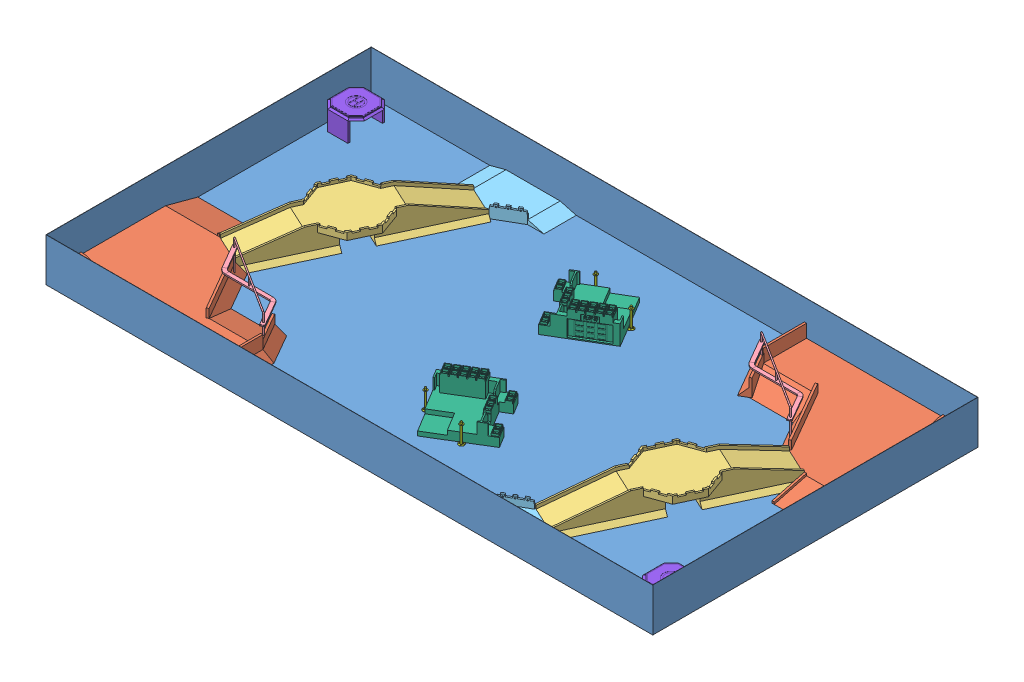
SolidWorks assembly RM场地总装, configuration 默认. Lengths in mm.
Overall size (28020 2000 15020).
17 component instances, 8 part files, 44 mates.
Components (placement in the parent):
- 场地底座-1: 场地底座 [默认] at (-5231.205 604.0435 28020) size (28020 2000 15020)
- 机器人启动区-1: 机器人启动区 [默认] at (-15231.205 614.0435 32770) x (0 0 1) z (-1 0 0) size (6992.82 1000 8400)
- 穿越桥-1: 穿越桥 [默认] at (-14265.56 1664.0435 26507.0583) x (-0.422618 0 0.906308) z (-0.906308 0 -0.422618) size (8806.06 1210 3000)
- 哨兵轨道-1: 哨兵轨道 [默认] at (-15148.1781 1894.0435 30872.3195) x (-0.5 0 -0.866025) z (0.866025 0 -0.5) size (4153.01 1720 2196.69)
- 关口-1: 关口 [默认] at (-11829.8568 614.0435 21918.3617) size (3992.82 610 2152.93)
- 关口-2: 关口 [默认] at (1367.4468 614.0435 34121.6383) x (-1 0 0) z (0 0 -1) size (3992.82 610 2152.93)
- 穿越桥-2: 穿越桥 [默认] at (3803.1499 1664.0435 29532.9417) x (0.422618 0 -0.906308) z (0.906308 0 0.422618) size (8806.06 1210 3000)
- 机器人启动区-2: 机器人启动区 [默认] at (4768.795 614.0435 23270) x (0 0 -1) z (1 0 0) size (6992.82 1000 8400)
- 哨兵轨道-2: 哨兵轨道 [默认] at (804.9132 1894.0435 22481.9287) x (-0.5 0 -0.866025) z (0.866025 0 -0.5) size (4153.01 1720 2196.69)
- rm资源岛-1: rm资源岛 [默认] at (-4093.3218 614.0435 31196.3435) x (-0.854584 0 0.519313) z (-0.519313 0 -0.854584) size (2750 1200 2570)
- rm资源岛-3: rm资源岛 [默认] at (-5345.3514 614.0435 24346.5388) x (0.859021 0 -0.51194) z (0.51194 0 0.859021) size (2750 1200 2570)
- 上岛立柱-1: 上岛立柱 [默认] at (-4055.4099 614.0435 23825.1634) x (0.859021 0 -0.51194) z (0.51194 0 0.859021) size (325 905 250)
- 四旋翼停机坪-1: 四旋翼停机坪 [默认] at (7918.795 1514.0435 33817.5787) x (0 0 -1) z (1 0 0) size (1700 1000 1700)
- 四旋翼停机坪-2: 四旋翼停机坪 [默认] at (-18381.205 1514.0435 22067.6477) x (0 0 -1) z (1 0 0) size (1700 1000 1700)
- 上岛立柱-2: 上岛立柱 [默认] at (-3321.3177 614.0435 32230.868) x (0.519313 0 0.854584) z (-0.854584 0 0.519313) size (325 905 250)
- 上岛立柱-3: 上岛立柱 [默认] at (-5378.7288 614.0435 31728.8001) x (-0.854584 0 0.519313) z (-0.519313 0 -0.854584) size (325 905 250)
- 上岛立柱-4: 上岛立柱 [默认] at (-6108.4243 614.0435 23305.4091) x (-0.51194 0 -0.859021) z (0.859021 0 -0.51194) size (325 905 250)
Mates (geometry in assembly coordinates):
- 重合2: coincident anti-aligned: plane of 机器人启动区-1 through (-15231.205 614.0435 32770) normal (0 -1 0); plane of 场地底座-1 through (-5231.205 614.0435 28020) normal (0 1 0)
- 重合3: coincident anti-aligned: plane of 场地底座-1 through (8768.795 2604.0435 35520) normal (0 0 -1); plane of 机器人启动区-1 through (-19231.205 1014.0435 35520) normal (0 0 1)
- 重合4: coincident anti-aligned: plane of 场地底座-1 through (-19231.205 2604.0435 20520) normal (1 0 0); plane of 机器人启动区-1 through (-19231.205 1014.0435 30020) normal (-1 0 0)
- 平行1: parallel aligned: plane of 场地底座-1 through (8778.795 2604.0435 35530) normal (0 0 1); plane of 哨兵轨道-1 through (-14217.7006 1864.0435 32278.9538) normal (0 0 1)
- 锁定1: lock: unknown of 机器人启动区-1; unknown of 哨兵轨道-1
- 重合9: coincident anti-aligned: plane of 场地底座-1 through (8768.795 2604.0435 20520) normal (0 0 1); plane of 关口-1 through (-13009.607 814.0435 20520) normal (0 0 -1)
- 重合10: coincident anti-aligned: plane of 场地底座-1 through (-5231.205 614.0435 28020) normal (0 1 0); plane of 关口-1 through (-11829.8568 614.0435 21918.3617) normal (0 -1 0)
- 重合14: coincident aligned: plane of 机器人启动区-2 through (4768.795 614.0435 23270) normal (0 -1 0); plane of 关口-2 through (1367.4468 614.0435 34121.6383) normal (0 -1 0)
- 重合15: coincident anti-aligned: plane of 机器人启动区-2 through (4768.795 614.0435 23270) normal (0 -1 0); plane of 场地底座-1 through (-5231.205 614.0435 28020) normal (0 1 0)
- 重合16: coincident anti-aligned: plane of 场地底座-1 through (8768.795 2604.0435 20520) normal (0 0 1); plane of 机器人启动区-2 through (8768.795 1014.0435 20520) normal (0 0 -1)
- 重合17: coincident anti-aligned: plane of 场地底座-1 through (8768.795 2604.0435 20520) normal (-1 0 0); plane of 机器人启动区-2 through (8768.795 1014.0435 26020) normal (1 0 0)
- 重合20: coincident anti-aligned: plane of 场地底座-1 through (-5231.205 614.0435 28020) normal (0 1 0); plane of 穿越桥-1 through (-7919.4238 614.0435 24412.5914) normal (0 -1 0)
- 重合21: coincident anti-aligned: plane of 机器人启动区-1 through (-16731.205 1014.0435 30020) normal (0.422618 0 -0.906308); plane of 穿越桥-1 through (-11641.0246 1014.0435 32393.5901) normal (-0.422618 0 0.906308)
- 重合22: coincident anti-aligned: line of 机器人启动区-1 through (-16731.205 1014.0435 30020) axis (0 -1 0); line of 穿越桥-1 through (-16731.205 814.0435 30020) axis (0 1 0)
- 重合25: coincident anti-aligned: plane of 穿越桥-1 through (-7919.4238 614.0435 24412.5914) normal (0.422618 0 -0.906308); plane of 关口-1 through (-13009.607 814.0435 22039) normal (-0.422618 0 0.906308)
- 重合26: coincident anti-aligned: plane of 场地底座-1 through (-5231.205 614.0435 28020) normal (0 1 0); plane of 穿越桥-2 through (-2542.9863 614.0435 31627.4086) normal (0 -1 0)
- 重合27: coincident anti-aligned: plane of 穿越桥-2 through (1178.6145 1014.0435 23646.4099) normal (0.422618 0 -0.906308); plane of 机器人启动区-2 through (6268.795 1014.0435 26020) normal (-0.422618 0 0.906308)
- 重合28: coincident anti-aligned: line of 穿越桥-2 through (6268.795 814.0435 26020) axis (0 1 0); line of 机器人启动区-2 through (6268.795 1014.0435 26020) axis (0 -1 0)
- 重合29: coincident anti-aligned: plane of 场地底座-1 through (8768.795 2604.0435 35520) normal (0 0 -1); plane of 关口-2 through (2547.1969 814.0435 35520) normal (0 0 1)
- 重合30: coincident anti-aligned: plane of 关口-2 through (2547.1969 814.0435 34001) normal (0.422618 0 -0.906308); plane of 穿越桥-2 through (-2542.9863 614.0435 31627.4086) normal (-0.422618 0 0.906308)
- 平行3: parallel aligned: plane of 哨兵轨道-1 through (-14217.7006 1864.0435 32098.9538) normal (0 0 -1); plane of 哨兵轨道-2 through (1735.3907 1864.0435 23708.563) normal (0 0 -1)
- 锁定2: lock: unknown of 机器人启动区-2; unknown of 哨兵轨道-2
- 重合31: coincident anti-aligned: plane of 场地底座-1 through (-5231.205 614.0435 28020) normal (0 1 0); plane of rm资源岛-1 through (-4093.3218 614.0435 31196.3435) normal (0 -1 0)
- 重合34: coincident anti-aligned: plane of 场地底座-1 through (-5231.205 614.0435 28020) normal (0 1 0); plane of rm资源岛-3 through (-5345.3514 614.0435 24346.5388) normal (0 -1 0)
- 重合37: coincident aligned: plane of 四旋翼停机坪-2 through (-18381.205 614.0435 22067.6477) normal (0 -1 0); plane of 四旋翼停机坪-1 through (7918.795 614.0435 33817.5787) normal (0 -1 0)
- 重合38: coincident anti-aligned: plane of 四旋翼停机坪-2 through (-18381.205 614.0435 22067.6477) normal (0 -1 0); plane of 场地底座-1 through (-5231.205 614.0435 28020) normal (0 1 0)
- 重合39: coincident: plane of 场地底座-1 through (-19231.205 2604.0435 20520) normal (1 0 0); line of 四旋翼停机坪-2 through (-19231.205 1514.0435 22534.0691) axis (0 0 -1)
- 重合40: coincident: plane of 场地底座-1 through (8768.795 2604.0435 20520) normal (-1 0 0); line of 四旋翼停机坪-1 through (8768.795 1514.0435 33351.1574) axis (0 0 1)
- 重合42: coincident aligned: plane of 上岛立柱-2 through (-3269.3864 614.0435 32316.3264) normal (0 -1 0); plane of 上岛立柱-3 through (-5464.1872 614.0435 31780.7314) normal (0 -1 0)
- 重合44: coincident aligned: plane of 上岛立柱-2 through (-3269.3864 614.0435 32316.3264) normal (0 -1 0); plane of 上岛立柱-1 through (-3969.5078 614.0435 23773.9694) normal (0 -1 0)
- 重合45: coincident aligned: plane of 上岛立柱-2 through (-3269.3864 614.0435 32316.3264) normal (0 -1 0); plane of 上岛立柱-4 through (-6159.6183 614.0435 23219.507) normal (0 -1 0)
- 重合48: coincident anti-aligned: plane of 场地底座-1 through (-5231.205 614.0435 28020) normal (0 1 0); plane of 上岛立柱-2 through (-3269.3864 614.0435 32316.3264) normal (0 -1 0)
- 重合49: coincident: plane of rm资源岛-1 through (-4601.0571 1014.0435 33008.5396) normal (0.519313 0 0.854584); line of 上岛立柱-2 through (-3323.4541 619.0435 32232.1662) axis (0.854584 0 -0.519313)
- 距离3: distance = 495 mm aligned: plane of 上岛立柱-2 through (-3292.2547 719.0435 32283.5081) normal (-0.854584 0 0.519313); plane of rm资源岛-1 through (-3746.4732 814.0435 32489.2263) normal (-0.854584 0 0.519313)
- 重合51: coincident: plane of rm资源岛-1 through (-5935.6922 1014.0435 30812.2588) normal (-0.854584 0 0.519313); line of 上岛立柱-3 through (-5380.0271 619.0435 31726.6637) axis (0.519313 0 0.854584)
- 距离4: distance = 495 mm aligned: plane of 上岛立柱-3 through (-5377.4305 719.0435 31730.9366) normal (0.519313 0 0.854584); plane of rm资源岛-1 through (-5120.3704 814.0435 32153.9556) normal (0.519313 0 0.854584)
- 重合53: coincident: plane of rm资源岛-3 through (-3506.3543 1014.0435 24746.4636) normal (0.859021 0 -0.51194); line of 上岛立柱-1 through (-4054.1301 619.0435 23827.3109) axis (-0.51194 0 -0.859021)
- 距离5: distance = 495 mm aligned: plane of 上岛立柱-1 through (-4056.6898 719.0435 23823.0158) normal (-0.51194 0 -0.859021); plane of rm资源岛-3 through (-4310.1 814.0435 23397.8003) normal (-0.51194 0 -0.859021)
- 重合55: coincident: plane of rm资源岛-3 through (-4822.04 1014.0435 22538.779) normal (-0.51194 0 -0.859021); line of 上岛立柱-4 through (-6106.2767 619.0435 23304.1293) axis (-0.859021 0 0.51194)
- 距离6: distance = 495 mm aligned: plane of rm资源岛-3 through (-5681.0612 814.0435 23050.719) normal (0.859021 0 -0.51194); plane of 上岛立柱-4 through (-6137.0332 719.0435 23252.5208) normal (0.859021 0 -0.51194)
- 锁定3: lock: unknown of 场地底座-1; unknown of rm资源岛-3
- 锁定4: lock: unknown of 场地底座-1; unknown of rm资源岛-1
- 锁定5: lock: unknown of 四旋翼停机坪-2; unknown of 场地底座-1
- 锁定6: lock: unknown of 四旋翼停机坪-2; unknown of 四旋翼停机坪-1
